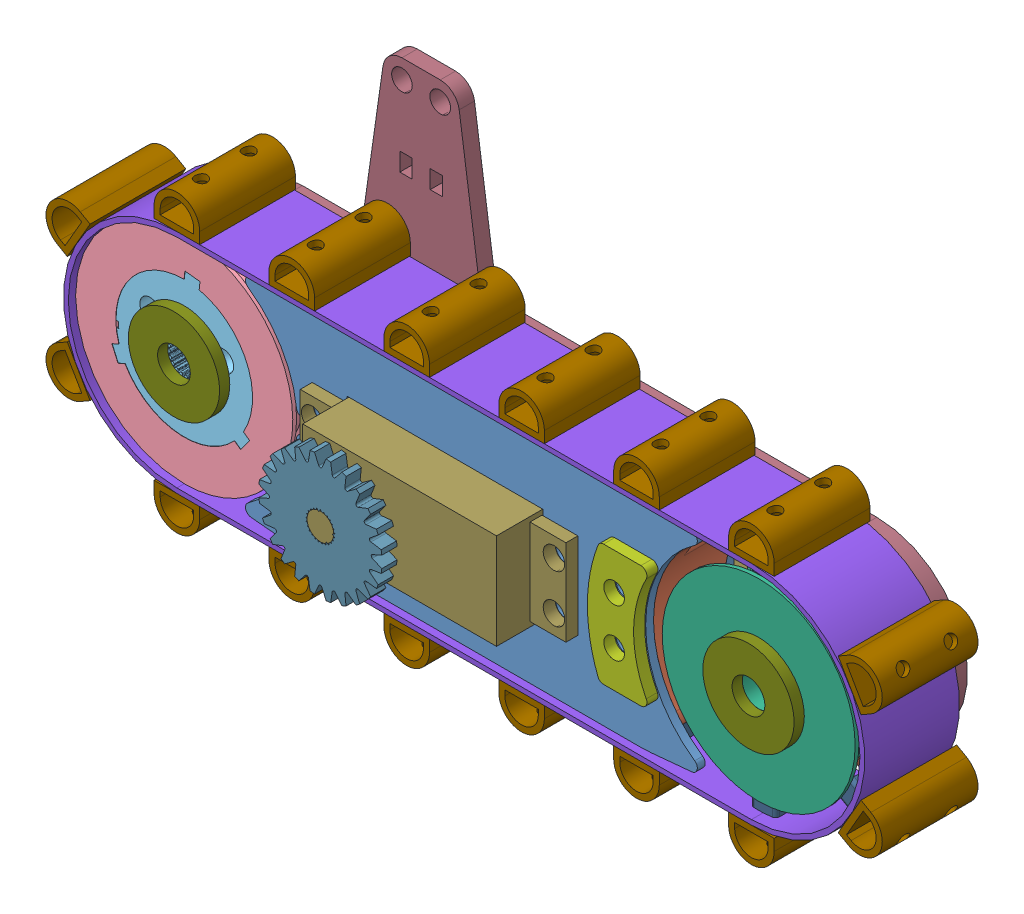
SolidWorks assembly DriveTread Assembly_R, configuration Default. Lengths in mm.
Overall size (178.18 86.46 42.8).
83 component instances, 16 part files, 31 mates.
Components (placement in the parent):
- tread runner-1: tread runner [Default] at (113.4402 41.5963 -20.788) x (-1 0 0) z (0 0 1) size (94.4 45.38 1.65)
- drive spacer_mid-1: drive spacer_mid [Default] at (14.0238 -0.101 -11.644) size (83.18 38.02 14.99)
- tread runner-2: tread runner [Default] at (113.4402 41.5963 -4.151) x (-1 0 0) z (0 0 1) size (94.4 45.38 1.65)
- drive spacer_out-1: drive spacer_out [Default] at (19.9176 6.2078 -23.9884) size (78.33 25.4 3.2)
- DriveWheel-4: DriveWheel [Default] at (2.8684 -8.3998 -56.4882) x (0.993984 -0.109528 0) z (0 0 1) size (45.38 45.43 18.29)
  - Custom Axle Drive_LEGO UWheel_6x3-1: Custom Axle Drive_LEGO UWheel_6x3 [Default] at (-5.8421 26.8291 44.8442) size (45.38 45.43 18.29)
  - WheelPlates w-Custom Axle-1: WheelPlates w-Custom Axle [Default] at (-5.8421 26.8291 50.737) x (0.5 -0.866025 0) z (0 0 1) size (28.95 30.08 3.2)
  - WheelPlates w-Custom Axle-2: WheelPlates w-Custom Axle [Default] at (-5.8421 26.8291 35.751) x (0.5 -0.866025 0) z (0 0 1) size (28.95 30.08 3.2)
- Custom Axle Float_LEGO UWheel_6xRR2-5: Custom Axle Float_LEGO UWheel_6xRR2 [Default] at (120.015 18.9078 -11.644) x (0.969727 -0.244192 0) z (0 0 1) size (40.3 40.3 18.29)
- drive spacer_in-4: drive spacer_in [Default] at (88.0272 6.2078 -2.3114) x (1 0 0) z (0 0 1) size (12.43 25.4 2.31)
- tread-2: tread [Default] at (0 -3.7808 -10.882) size (178.18 61.66 20)
  - tread_base-1: tread_base [Default] at origin size (167.39 47.38 19.81)
  - D-Lug_Terrain-1: D-Lug_Terrain [Default] at (0 48.7584 -10.094) size (9.53 7.14 20)
  - D-Lug_Terrain-2: D-Lug_Terrain [Default] at (-22.5771 35.7234 -10.094) x (0.5 0.866025 0) z (0 0 1) size (9.53 7.14 20)
  - D-Lug_Terrain-3: D-Lug_Terrain [Default] at (-22.5771 9.6536 -10.094) x (-0.5 0.866025 0) z (0 0 1) size (9.53 7.14 20)
  - D-Lug_Terrain-4: D-Lug_Terrain [Default] at (0 -3.3813 -10.094) x (-1 0 0) z (0 0 1) size (9.53 7.14 20)
  - D-Lug_Terrain-6: D-Lug_Terrain [Default] at (24.003 48.7584 -10.094) size (9.53 7.14 20)
  - D-Lug_Terrain-7: D-Lug_Terrain [Default] at (48.006 48.7584 -10.094) size (9.53 7.14 20)
  - D-Lug_Terrain-8: D-Lug_Terrain [Default] at (72.009 48.7584 -10.094) size (9.53 7.14 20)
  - D-Lug_Terrain-9: D-Lug_Terrain [Default] at (96.012 48.7584 -10.094) size (9.53 7.14 20)
  - D-Lug_Terrain-10: D-Lug_Terrain [Default] at (120.015 48.7584 -10.094) size (9.53 7.14 20)
  - D-Lug_Terrain-11: D-Lug_Terrain [Default] at (24.003 -3.3813 -10.094) x (-1 0 0) z (0 0 1) size (9.53 7.14 20)
  - D-Lug_Terrain-12: D-Lug_Terrain [Default] at (48.006 -3.3813 -10.094) x (-1 0 0) z (0 0 1) size (9.53 7.14 20)
  - D-Lug_Terrain-13: D-Lug_Terrain [Default] at (72.009 -3.3813 -10.094) x (-1 0 0) z (0 0 1) size (9.53 7.14 20)
  - D-Lug_Terrain-14: D-Lug_Terrain [Default] at (96.012 -3.3813 -10.094) x (-1 0 0) z (0 0 1) size (9.53 7.14 20)
  - D-Lug_Terrain-15: D-Lug_Terrain [Default] at (142.5921 35.7234 -10.094) x (0.5 -0.866025 0) z (0 0 1) size (9.53 7.14 20)
  - D-Lug_Terrain-16: D-Lug_Terrain [Default] at (142.5921 9.6536 -10.094) x (-0.5 -0.866025 0) z (0 0 1) size (9.53 7.14 20)
  - D-Lug_Terrain-17: D-Lug_Terrain [Default] at (120.015 -3.3813 -10.094) x (-1 0 0) z (0 0 1) size (9.53 7.14 20)
  - DriveLug_x-1: DriveLug_x [Default] at (-2.7045 0 0) size (5.84 6.24 14.92)
    - Drive Lug_x-1: Drive Lug_x [Default] at origin size (5.41 3.2 14.92)
    - 97334A104_NYLON SOCKET HEAD CAP SCREW-1: 97334A104_NYLON SOCKET HEAD CAP SCREW [97334A104] at (2.7045 0.0254 0) x (0.302379 0 0.953188) z (0 -1 0) size (4.65 4.65 6.24)
  - DriveLug_x-2: DriveLug_x [Default] at (-21.0011 13.6864 0) x (0.5 -0.866025 0) z (0 0 1) size (5.84 6.24 14.92)
    - Drive Lug_x-1: Drive Lug_x [Default] at origin size (5.41 3.2 14.92)
    - 97334A104_NYLON SOCKET HEAD CAP SCREW-1: 97334A104_NYLON SOCKET HEAD CAP SCREW [97334A104] at (2.7045 0.0254 0) x (0.302379 0 0.953188) z (0 -1 0) size (4.65 4.65 6.24)
  - DriveLug_x-3: DriveLug_x [Default] at (-18.2966 36.375 0) x (-0.5 -0.866025 0) z (0 0 1) size (5.84 6.24 14.92)
    - Drive Lug_x-1: Drive Lug_x [Default] at origin size (5.41 3.2 14.92)
    - 97334A104_NYLON SOCKET HEAD CAP SCREW-1: 97334A104_NYLON SOCKET HEAD CAP SCREW [97334A104] at (2.7045 0.0254 0) x (0.302379 0 0.953188) z (0 -1 0) size (4.65 4.65 6.24)
  - DriveLug_x-4: DriveLug_x [Default] at (2.7045 45.3771 0) x (-1 0 0) z (0 0 1) size (5.84 6.24 14.92)
    - Drive Lug_x-1: Drive Lug_x [Default] at origin size (5.41 3.2 14.92)
    - 97334A104_NYLON SOCKET HEAD CAP SCREW-1: 97334A104_NYLON SOCKET HEAD CAP SCREW [97334A104] at (2.7045 0.0254 0) x (0.302379 0 0.953188) z (0 -1 0) size (4.65 4.65 6.24)
  - DriveLug_x-5: DriveLug_x [Default] at (21.2985 0 0) size (5.84 6.24 14.92)
    - Drive Lug_x-1: Drive Lug_x [Default] at origin size (5.41 3.2 14.92)
    - 97334A104_NYLON SOCKET HEAD CAP SCREW-1: 97334A104_NYLON SOCKET HEAD CAP SCREW [97334A104] at (2.7045 0.0254 0) x (0.302379 0 0.953188) z (0 -1 0) size (4.65 4.65 6.24)
  - DriveLug_x-6: DriveLug_x [Default] at (45.3015 0 0) size (5.84 6.24 14.92)
    - Drive Lug_x-1: Drive Lug_x [Default] at origin size (5.41 3.2 14.92)
    - 97334A104_NYLON SOCKET HEAD CAP SCREW-1: 97334A104_NYLON SOCKET HEAD CAP SCREW [97334A104] at (2.7045 0.0254 0) x (0.302379 0 0.953188) z (0 -1 0) size (4.65 4.65 6.24)
  - DriveLug_x-7: DriveLug_x [Default] at (69.3045 0 0) size (5.84 6.24 14.92)
    - Drive Lug_x-1: Drive Lug_x [Default] at origin size (5.41 3.2 14.92)
    - 97334A104_NYLON SOCKET HEAD CAP SCREW-1: 97334A104_NYLON SOCKET HEAD CAP SCREW [97334A104] at (2.7045 0.0254 0) x (0.302379 0 0.953188) z (0 -1 0) size (4.65 4.65 6.24)
  - DriveLug_x-8: DriveLug_x [Default] at (93.3075 0 0) size (5.84 6.24 14.92)
    - Drive Lug_x-1: Drive Lug_x [Default] at origin size (5.41 3.2 14.92)
    - 97334A104_NYLON SOCKET HEAD CAP SCREW-1: 97334A104_NYLON SOCKET HEAD CAP SCREW [97334A104] at (2.7045 0.0254 0) x (0.302379 0 0.953188) z (0 -1 0) size (4.65 4.65 6.24)
  - DriveLug_x-9: DriveLug_x [Default] at (117.3105 0 0) size (5.84 6.24 14.92)
    - Drive Lug_x-1: Drive Lug_x [Default] at origin size (5.41 3.2 14.92)
    - 97334A104_NYLON SOCKET HEAD CAP SCREW-1: 97334A104_NYLON SOCKET HEAD CAP SCREW [97334A104] at (2.7045 0.0254 0) x (0.302379 0 0.953188) z (0 -1 0) size (4.65 4.65 6.24)
  - DriveLug_x-10: DriveLug_x [Default] at (138.3116 9.0021 0) x (0.5 0.866025 0) z (0 0 1) size (5.84 6.24 14.92)
    - Drive Lug_x-1: Drive Lug_x [Default] at origin size (5.41 3.2 14.92)
    - 97334A104_NYLON SOCKET HEAD CAP SCREW-1: 97334A104_NYLON SOCKET HEAD CAP SCREW [97334A104] at (2.7045 0.0254 0) x (0.302379 0 0.953188) z (0 -1 0) size (4.65 4.65 6.24)
  - DriveLug_x-11: DriveLug_x [Default] at (141.0161 31.6907 0) x (-0.5 0.866025 0) z (0 0 1) size (5.84 6.24 14.92)
    - Drive Lug_x-1: Drive Lug_x [Default] at origin size (5.41 3.2 14.92)
    - 97334A104_NYLON SOCKET HEAD CAP SCREW-1: 97334A104_NYLON SOCKET HEAD CAP SCREW [97334A104] at (2.7045 0.0254 0) x (0.302379 0 0.953188) z (0 -1 0) size (4.65 4.65 6.24)
  - DriveLug_x-12: DriveLug_x [Default] at (122.7195 45.3771 0) x (-1 0 0) z (0 0 1) size (5.84 6.24 14.92)
    - Drive Lug_x-1: Drive Lug_x [Default] at origin size (5.41 3.2 14.92)
    - 97334A104_NYLON SOCKET HEAD CAP SCREW-1: 97334A104_NYLON SOCKET HEAD CAP SCREW [97334A104] at (2.7045 0.0254 0) x (0.302379 0 0.953188) z (0 -1 0) size (4.65 4.65 6.24)
  - DriveLug_x-13: DriveLug_x [Default] at (26.7075 45.3771 0) x (-1 0 0) z (0 0 1) size (5.84 6.24 14.92)
    - Drive Lug_x-1: Drive Lug_x [Default] at origin size (5.41 3.2 14.92)
    - 97334A104_NYLON SOCKET HEAD CAP SCREW-1: 97334A104_NYLON SOCKET HEAD CAP SCREW [97334A104] at (2.7045 0.0254 0) x (0.302379 0 0.953188) z (0 -1 0) size (4.65 4.65 6.24)
  - DriveLug_x-14: DriveLug_x [Default] at (50.7105 45.3771 0) x (-1 0 0) z (0 0 1) size (5.84 6.24 14.92)
    - Drive Lug_x-1: Drive Lug_x [Default] at origin size (5.41 3.2 14.92)
    - 97334A104_NYLON SOCKET HEAD CAP SCREW-1: 97334A104_NYLON SOCKET HEAD CAP SCREW [97334A104] at (2.7045 0.0254 0) x (0.302379 0 0.953188) z (0 -1 0) size (4.65 4.65 6.24)
  - DriveLug_x-15: DriveLug_x [Default] at (74.7135 45.3771 0) x (-1 0 0) z (0 0 1) size (5.84 6.24 14.92)
    - Drive Lug_x-1: Drive Lug_x [Default] at origin size (5.41 3.2 14.92)
    - 97334A104_NYLON SOCKET HEAD CAP SCREW-1: 97334A104_NYLON SOCKET HEAD CAP SCREW [97334A104] at (2.7045 0.0254 0) x (0.302379 0 0.953188) z (0 -1 0) size (4.65 4.65 6.24)
  - DriveLug_x-16: DriveLug_x [Default] at (98.7165 45.3771 0) x (-1 0 0) z (0 0 1) size (5.84 6.24 14.92)
    - Drive Lug_x-1: Drive Lug_x [Default] at origin size (5.41 3.2 14.92)
    - 97334A104_NYLON SOCKET HEAD CAP SCREW-1: 97334A104_NYLON SOCKET HEAD CAP SCREW [97334A104] at (2.7045 0.0254 0) x (0.302379 0 0.953188) z (0 -1 0) size (4.65 4.65 6.24)
- Servo_ContRotation-4: Servo_ContRotation [Default] at (74.747 8.9078 -2.5) x (0 1 0) z (0 0 1) size (20 55.5 42.8)
- drive plate_out-2: drive plate_out [Default] at (0 0 -27.1888) size (157.83 74.53 3.2)
- 24T Gear _Futaba Spline-2: 24T Gear _Futaba Spline [Default] at (44.647 18.9078 10.5017) size (25.67 25.67 3.2)
- wheelspacer_out-1: wheelspacer_out [Default] at (120.015 18.9078 -23.9884) size (19.05 19.05 3.2)
- wheelspacer_out-2: wheelspacer_out [Default] at (0 18.9078 -23.9884) size (19.05 19.05 3.2)
- wheelspacer_in-1: wheelspacer_in [Default] at (120.015 18.9078 -2.5) size (19.05 19.05 2.13)
- wheelspacer_in-2: wheelspacer_in [Default] at (0 18.9078 -2.5) size (19.05 19.05 2.13)
Mates (geometry in assembly coordinates):
- Coincident6: coincident: plane of tread runner-1 through (120.015 18.9078 -19.137) normal (0 0 1); plane of drive spacer_mid-1 through (0 18.9078 -19.137) normal (0 0 -1)
- Coincident8: coincident: plane of drive spacer_mid-1 through (0 18.9078 -4.151) normal (0 0 1); plane of tread runner-2 through (120.015 18.9078 -4.151) normal (0 0 -1)
- Concentric15: concentric: cylinder of drive spacer_mid-1 through (29.247 13.9078 -25.2436) axis (0 0 1) radius 2.159; cylinder of tread runner-2 through (29.247 13.9078 -10.2576) axis (0 0 1) radius 2.159
- Concentric17: concentric: cylinder of tread runner-2 through (29.247 13.9078 -10.2576) axis (0 0 1) radius 2.159; cylinder of drive spacer_out-1 through (29.247 13.9078 -30.095) axis (0 0 1) radius 2.159
- Concentric18: concentric: cylinder of tread runner-2 through (79.747 23.9078 -10.2576) axis (0 0 1) radius 2.159; cylinder of drive spacer_out-1 through (79.747 23.9078 -30.095) axis (0 0 1) radius 2.159
- Concentric39: concentric: cylinder of tread runner-1 through (79.747 13.9078 -26.8946) axis (0 0 1) radius 2.159; cylinder of drive spacer_mid-1 through (79.747 13.9078 -25.2436) axis (0 0 1) radius 2.159
- Concentric40: concentric: cylinder of tread runner-1 through (29.247 23.9078 -26.8946) axis (0 0 1) radius 2.159; cylinder of drive spacer_mid-1 through (29.247 23.9078 -25.2436) axis (0 0 1) radius 2.159
- Parallel4: parallel: plane of tread runner-1 through (113.4402 41.5963 -19.137) normal (0 1 0); plane of drive spacer_in-4 through (100.0974 31.6078 0) normal (0 1 0)
- Concentric62: concentric: cylinder of drive spacer_mid-1 through (92.3222 23.9078 -25.2436) axis (0 0 1) radius 2.159; cylinder of tread runner-2 through (92.3222 23.9078 -10.2576) axis (0 0 1) radius 2.159
- Coincident34: coincident: plane of Custom Axle Float_LEGO UWheel_6xRR2-5 through (120.015 18.9078 -20.788) normal (0 0 -1); plane of tread-2/tread_base-1 through (120.015 18.9078 -20.788) normal (0 0 -1)
- Coincident39: coincident: plane of tread runner-1 through (120.015 18.9078 -20.788) normal (0 0 -1); plane of drive spacer_out-1 through (0 18.9078 -20.788) normal (0 0 1)
- Coincident40: coincident: plane of tread runner-2 through (120.015 18.9078 -2.5) normal (0 0 1); plane of Servo_ContRotation-4 through (74.747 8.9078 -2.5) normal (0 0 -1)
- Concentric67: concentric: cylinder of tread runner-2 through (92.3222 13.9078 -10.2576) axis (0 0 1) radius 2.159; cylinder of drive spacer_in-4 through (92.3222 13.9078 0) axis (0 0 -1) radius 2.159
- Parallel6: parallel: cylinder of tread runner-2 through (92.3222 23.9078 -10.2576) axis (0 0 1) radius 2.159; cylinder of drive spacer_in-4 through (92.3222 23.9078 0) axis (0 0 -1) radius 2.159
- Coincident46: coincident: plane of drive spacer_out-1 through (0 18.9078 -23.9884) normal (0 0 -1); plane of drive plate_out-2 through (0 18.9078 -23.9884) normal (0 0 1)
- Concentric73: concentric: cylinder of drive spacer_out-1 through (29.247 23.9078 -30.095) axis (0 0 1) radius 2.159; cylinder of drive plate_out-2 through (29.247 23.9078 -23.9884) axis (0 0 -1) radius 2.159
- Concentric74: concentric: cylinder of tread runner-1 through (92.3222 13.9078 -26.8946) axis (0 0 1) radius 2.159; cylinder of drive plate_out-2 through (92.3222 13.9078 -23.9884) axis (0 0 -1) radius 2.159
- Coincident53: coincident: plane of Servo_ContRotation-4 through (44.647 18.9078 13.7021) normal (0 0 1); plane of 24T Gear _Futaba Spline-2 through (44.647 18.9078 13.7021) normal (0 0 1)
- Concentric84: concentric: cylinder of Servo_ContRotation-4 through (44.647 18.9078 13.7021) axis (0 0 -1) radius 2.794; circle of 24T Gear _Futaba Spline-2
- Coincident56: coincident: plane of DriveWheel-4/Custom Axle Drive_LEGO UWheel_6x3-1 through (0 18.9078 -20.788) normal (0 0 -1); plane of Custom Axle Float_LEGO UWheel_6xRR2-5 through (120.015 18.9078 -20.788) normal (0 0 -1)
- Coincident58: coincident: plane of tread runner-2 through (120.015 18.9078 -2.5) normal (0 0 1); plane of Custom Axle Float_LEGO UWheel_6xRR2-5 through (120.015 18.9078 -2.5) normal (0 0 1)
- Concentric88: concentric: cylinder of DriveWheel-4/Custom Axle Drive_LEGO UWheel_6x3-1 through (0 18.9078 -15.454) axis (0 0 1) radius 15.9245; cylinder of tread-2/tread_base-1 through (0 18.9078 -0.976) axis (0 0 -1) radius 22.6885
- Concentric89: concentric: cylinder of Custom Axle Float_LEGO UWheel_6xRR2-5 through (120.015 18.9078 -14.6943) axis (0 0 1) radius 13.3845; cylinder of tread-2/tread_base-1 through (120.015 18.9078 -0.976) axis (0 0 -1) radius 22.6885
- Coincident59: coincident: plane of Custom Axle Float_LEGO UWheel_6xRR2-5 through (120.015 18.9078 -20.788) normal (0 0 -1); plane of wheelspacer_out-1 through (120.015 18.9078 -20.788) normal (0 0 1)
- Concentric90: concentric: cylinder of Custom Axle Float_LEGO UWheel_6xRR2-5 through (120.015 18.9078 -2.5) axis (0 0 -1) radius 3.429; cylinder of wheelspacer_out-1 through (120.015 18.9078 -20.788) axis (0 0 -1) radius 3.429
- Coincident60: coincident: plane of DriveWheel-4/Custom Axle Drive_LEGO UWheel_6x3-1 through (0 18.9078 -20.788) normal (0 0 -1); plane of wheelspacer_out-2 through (0 18.9078 -20.788) normal (0 0 1)
- Concentric91: concentric: cylinder of drive plate_out-2 through (0 18.9078 -23.9884) axis (0 0 -1) radius 2.54; cylinder of wheelspacer_out-2 through (0 18.9078 -20.788) axis (0 0 -1) radius 9.525
- Coincident61: coincident: plane of Custom Axle Float_LEGO UWheel_6xRR2-5 through (120.015 18.9078 -2.5) normal (0 0 1); plane of wheelspacer_in-1 through (120.015 18.9078 -2.5) normal (0 0 -1)
- Concentric92: concentric: cylinder of Custom Axle Float_LEGO UWheel_6xRR2-5 through (120.015 18.9078 -2.5) axis (0 0 -1) radius 3.429; cylinder of wheelspacer_in-1 through (120.015 18.9078 -0.3664) axis (0 0 -1) radius 3.429
- Coincident62: coincident: plane of DriveWheel-4/Custom Axle Drive_LEGO UWheel_6x3-1 through (0 18.9078 -2.5) normal (0 0 1); plane of wheelspacer_in-2 through (0 18.9078 -2.5) normal (0 0 -1)
- Concentric93: concentric: cylinder of drive plate_out-2 through (0 18.9078 -23.9884) axis (0 0 -1) radius 2.54; cylinder of wheelspacer_in-2 through (0 18.9078 -0.3664) axis (0 0 -1) radius 3.429
